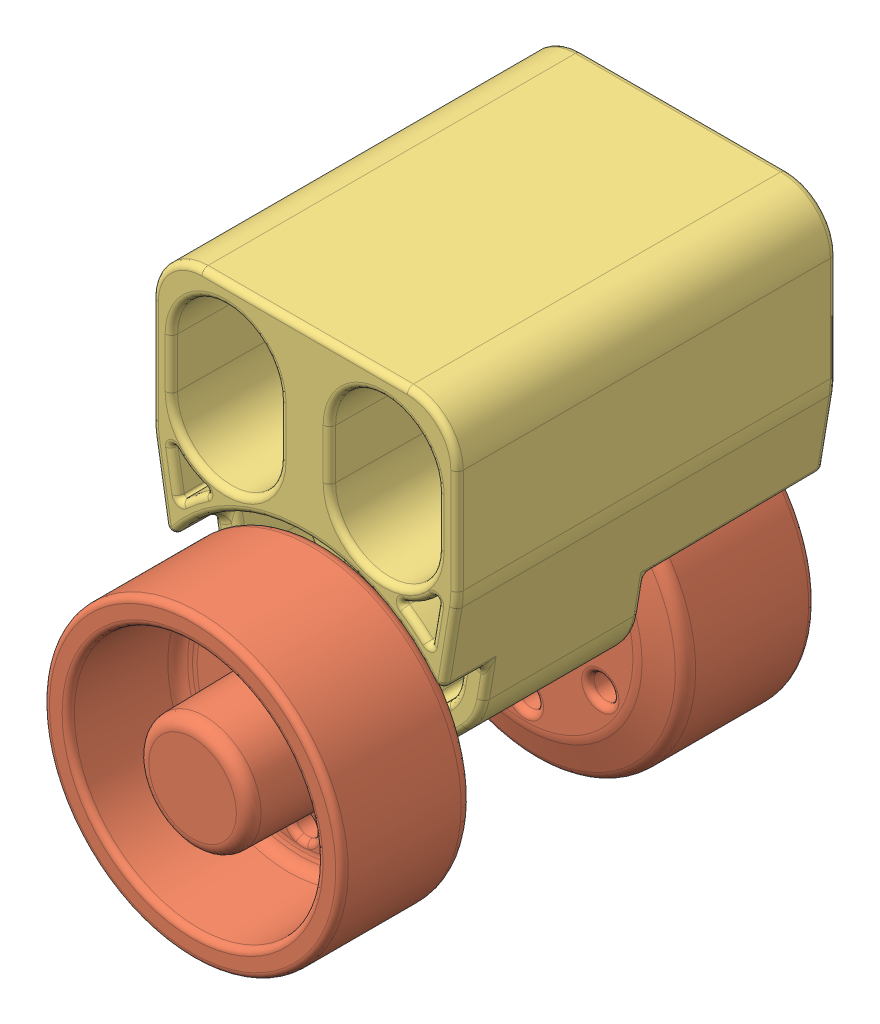
SolidWorks assembly IDLER-WHEEL, configuration Default. Lengths in mm.
Overall size (24.62 39.5 39.51).
4 component instances, 3 part files, 0 mates.
Components (placement in the parent):
- IDLER-WHEEL-AXLE_1-1: IDLER-WHEEL-AXLE_1 [Default] at (0 -19.5 0) size (4 4 34)
- IDLER-WHEEL-ROLLER_1-1: IDLER-WHEEL-ROLLER_1 [Default] at (0 -19.5 -6.5) x (0 0 -1) z (0 1 0) size (12.5 24 24)
- IDLER-WHEEL-SUPPORT-1: IDLER-WHEEL-SUPPORT [Default] at origin size (24.62 32.5 30.52)
- IDLER-WHEEL-ROLLER_1-2: IDLER-WHEEL-ROLLER_1 [Default] at (0 -19.5 6.5) x (0 0 1) z (0 1 0) size (12.5 24 24)
